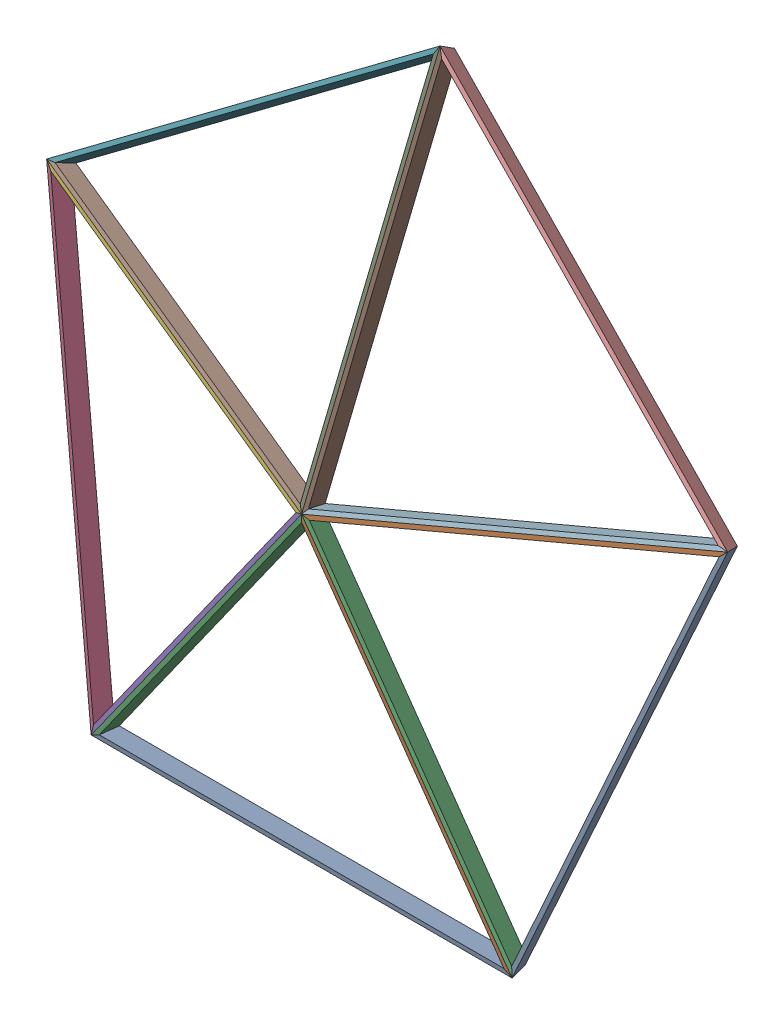
SolidWorks assembly pent_2, configuration Default. Lengths in mm.
Overall size (6293.97 5914.38 3795.98).
20 component instances, 3 part files, 0 mates.
Components (placement in the parent):
- pent_1_1-1: pent_1_1 [Default] at origin size (2962.34 3017 2240.7)
  - dome-pent_A_1-1: dome-pent_A_1 [Default] at (0 441.1426 -6109.298) x (0.467086 -0.498272 0.730449) z (-0.809017 -0.574201 0.125638) size (1245.79 955.59 2041.73)
  - dome-pent_B_1-1: dome-pent_B_1 [Default] at (0 441.1426 -6109.298) x (0.467086 -0.498272 0.730449) z (-0.809017 -0.574201 0.125638) size (1537.41 1660.3 24.8)
  - dome-pent_C_1-1: dome-pent_C_1 [Default] at (0 441.1426 -6109.298) x (0.467086 -0.498272 0.730449) z (-0.809017 -0.574201 0.125638) size (368.77 775.55 2041.73)
- pent_1_1-2: pent_1_1 [Default] at (-1651.7981 1172.3656 -256.5205) x (0.309017 -0.929076 0.203287) z (-0.203287 0.144283 0.96843) size (2962.34 3017 2240.7)
  - dome-pent_A_1-1: dome-pent_A_1 [Default] at (0 441.1426 -6109.298) x (0.467086 -0.498272 0.730449) z (-0.809017 -0.574201 0.125638) size (1245.79 955.59 2041.73)
  - dome-pent_B_1-1: dome-pent_B_1 [Default] at (0 441.1426 -6109.298) x (0.467086 -0.498272 0.730449) z (-0.809017 -0.574201 0.125638) size (1537.41 1660.3 24.8)
  - dome-pent_C_1-1: dome-pent_C_1 [Default] at (0 441.1426 -6109.298) x (0.467086 -0.498272 0.730449) z (-0.809017 -0.574201 0.125638) size (368.77 775.55 2041.73)
- pent_1_1-3: pent_1_1 [Default] at (-1020.8674 3069.293 -671.5793) x (-0.809017 -0.574201 0.125638) z (-0.125638 0.377739 0.917349) size (2962.34 3017 2240.7)
  - dome-pent_A_1-1: dome-pent_A_1 [Default] at (0 441.1426 -6109.298) x (0.467086 -0.498272 0.730449) z (-0.809017 -0.574201 0.125638) size (1245.79 955.59 2041.73)
  - dome-pent_B_1-1: dome-pent_B_1 [Default] at (0 441.1426 -6109.298) x (0.467086 -0.498272 0.730449) z (-0.809017 -0.574201 0.125638) size (1537.41 1660.3 24.8)
  - dome-pent_C_1-1: dome-pent_C_1 [Default] at (0 441.1426 -6109.298) x (0.467086 -0.498272 0.730449) z (-0.809017 -0.574201 0.125638) size (368.77 775.55 2041.73)
- pent_1_1-4: pent_1_1 [Default] at (1020.8674 3069.293 -671.5793) x (-0.809017 0.574201 -0.125638) z (0.125638 0.377739 0.917349) size (2962.34 3017 2240.7)
  - dome-pent_A_1-1: dome-pent_A_1 [Default] at (0 441.1426 -6109.298) x (0.467086 -0.498272 0.730449) z (-0.809017 -0.574201 0.125638) size (1245.79 955.59 2041.73)
  - dome-pent_B_1-1: dome-pent_B_1 [Default] at (0 441.1426 -6109.298) x (0.467086 -0.498272 0.730449) z (-0.809017 -0.574201 0.125638) size (1537.41 1660.3 24.8)
  - dome-pent_C_1-1: dome-pent_C_1 [Default] at (0 441.1426 -6109.298) x (0.467086 -0.498272 0.730449) z (-0.809017 -0.574201 0.125638) size (368.77 775.55 2041.73)
- pent_1_1-5: pent_1_1 [Default] at (1651.7981 1172.3656 -256.5205) x (0.309017 0.929076 -0.203287) z (0.203287 0.144283 0.96843) size (2962.34 3017 2240.7)
  - dome-pent_A_1-1: dome-pent_A_1 [Default] at (0 441.1426 -6109.298) x (0.467086 -0.498272 0.730449) z (-0.809017 -0.574201 0.125638) size (1245.79 955.59 2041.73)
  - dome-pent_B_1-1: dome-pent_B_1 [Default] at (0 441.1426 -6109.298) x (0.467086 -0.498272 0.730449) z (-0.809017 -0.574201 0.125638) size (1537.41 1660.3 24.8)
  - dome-pent_C_1-1: dome-pent_C_1 [Default] at (0 441.1426 -6109.298) x (0.467086 -0.498272 0.730449) z (-0.809017 -0.574201 0.125638) size (368.77 775.55 2041.73)
